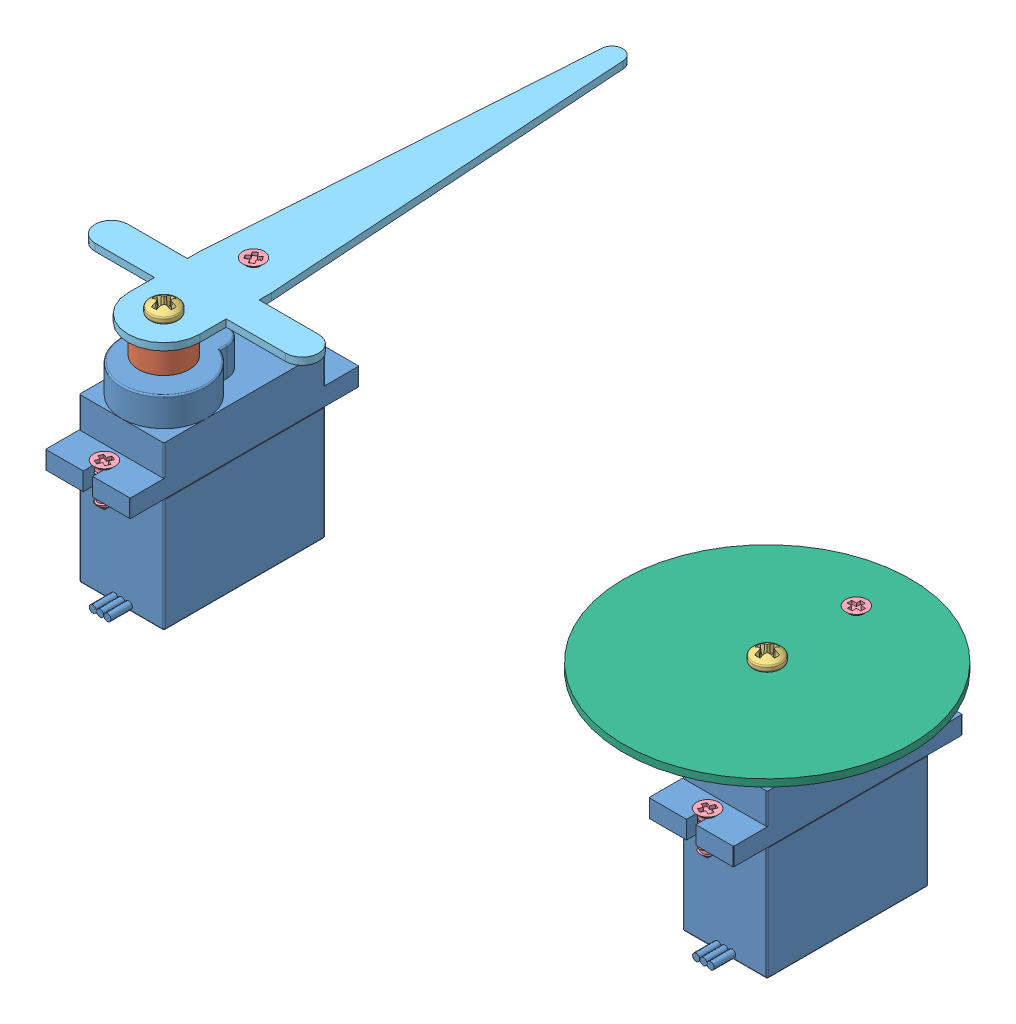
SolidWorks assembly AC, configuration Predeterminado. Lengths in mm.
Overall size (119.83 34.06 84.1).
14 component instances, 6 part files, 24 mates.
Components (placement in the parent):
- sg90-1: sg90 [Default] at (182.9409 -195.7135 134.2781) x (0 0 -1) z (1 0 0) size (31.9 29.9 11.8)
- sg90-2: sg90 [Default] at (98.7972 -195.7135 134.2781) x (0 0 -1) z (1 0 0) size (31.9 29.9 11.8)
- SG90 plastic Horn-1: SG90 plastic Horn [Default] at (188.8409 -166.2635 128.3781) x (-0.029359 0 -0.999569) z (0.999569 0 -0.029359) size (19.4 4 7.07)
- SG90 plastic Horn-2: SG90 plastic Horn [Default] at (104.6972 -166.2635 128.3781) x (-0.012387 0 -0.999923) z (0.999923 0 -0.012387) size (19.4 4 7.07)
- (M2_3_mm)_90116A007_METRIC 316 SS PAN HEAD PHILLIPS MACHINE SCREW-1: (M2_3_mm)_90116A007_METRIC 316 SS PAN HEAD PHILLIPS MACHINE SCREW [90116A007] at (104.6972 -166.2635 128.3781) x (-1 0 0) z (0 1 0) size (4 4 4.68)
- (M2_3_mm)_90116A007_METRIC 316 SS PAN HEAD PHILLIPS MACHINE SCREW-2: (M2_3_mm)_90116A007_METRIC 316 SS PAN HEAD PHILLIPS MACHINE SCREW [90116A007] at (188.8409 -166.2635 128.3781) x (-1 0 0) z (0 1 0) size (4 4 4.68)
- M2x6 SelfTap Screw-1: M2x6 SelfTap Screw [Predeterminado] at (104.6972 -162.7635 115.8781) x (0.825172 0 -0.564882) z (0 1 0) size (3.4 3.28 6)
- M2x6 SelfTap Screw-2: M2x6 SelfTap Screw [Predeterminado] at (188.7787 -162.7635 115.8783) x (0.001298 0 -0.999999) z (0 1 0) size (3.4 3.28 6)
- M2x6 SelfTap Screw-3: M2x6 SelfTap Screw [Predeterminado] at (104.6972 -176.8135 109.3781) x (-0.923728 0 -0.383049) z (0 1 0) size (3.4 3.28 6)
- M2x6 SelfTap Screw-4: M2x6 SelfTap Screw [Predeterminado] at (104.6972 -176.8135 136.6781) x (-0.923728 0 -0.383049) z (0 1 0) size (3.4 3.28 6)
- M2x6 SelfTap Screw-5: M2x6 SelfTap Screw [Predeterminado] at (188.8409 -176.8135 136.6781) x (0.923728 0 0.383049) z (0 1 0) size (3.4 3.28 6)
- M2x6 SelfTap Screw-6: M2x6 SelfTap Screw [Predeterminado] at (188.8409 -176.8135 109.3781) x (0.923728 0 0.383049) z (0 1 0) size (3.4 3.28 6)
- Sword-1: Sword [Predeterminado] at (59.4912 -163.2635 112.6165) x (1 0 0) z (0 1 0) size (31.17 69 1)
- Shield-1: Shield [Predeterminado] at (233.9679 -164.2635 112.3919) x (-0.999988 0 0.004973) z (0 -1 0) size (40 40 1)
Mates (geometry in assembly coordinates):
- Coincidente272: coincident: plane of sg90-1 through (188.8409 -165.8135 128.3781) normal (0 1 0); plane of SG90 plastic Horn-1 through (188.8043 -165.8135 127.1336) normal (0 -1 0)
- Concéntrica139: concentric: circle of sg90-1; circle of SG90 plastic Horn-1
- Concéntrica159: concentric: circle of sg90-1; circle of M2x6 SelfTap Screw-5
- Distancia35: distance = 0.5 mm: plane of M2x6 SelfTap Screw-5 through (188.8409 -176.8135 136.6781) normal (0 1 0); plane of sg90-1 through (182.9409 -177.3135 138.9781) normal (0 1 0)
- Concéntrica160: concentric: circle of sg90-1; circle of M2x6 SelfTap Screw-6
- Distancia36: distance = 0.5 mm: plane of M2x6 SelfTap Screw-6 through (188.8409 -176.8135 109.3781) normal (0 1 0); plane of sg90-1 through (194.7409 -177.3135 107.0781) normal (0 1 0)
- Coincidente273: coincident: plane of sg90-2 through (104.6972 -165.8135 128.3781) normal (0 1 0); plane of SG90 plastic Horn-2 through (104.6818 -165.8135 127.1332) normal (0 -1 0)
- Concéntrica140: concentric: circle of sg90-2; circle of SG90 plastic Horn-2
- Concéntrica161: concentric: circle of sg90-2; circle of M2x6 SelfTap Screw-4
- Distancia37: distance = 0.5 mm: plane of M2x6 SelfTap Screw-4 through (104.6972 -176.8135 136.6781) normal (0 1 0); plane of sg90-2 through (98.7972 -177.3135 138.9781) normal (0 1 0)
- Distancia38: distance = 0.5 mm: plane of M2x6 SelfTap Screw-3 through (104.6972 -176.8135 109.3781) normal (0 1 0); plane of sg90-2 through (110.5972 -177.3135 107.0781) normal (0 1 0)
- Concéntrica162: concentric: circle of sg90-2; circle of M2x6 SelfTap Screw-3
- Coincidente325: coincident: plane of SG90 plastic Horn-1 through (188.7371 -164.2635 124.8446) normal (0 1 0); plane of Shield-1 through (188.8409 -164.2635 128.3781) normal (0 -1 0)
- Concéntrica165: concentric: circle of SG90 plastic Horn-1; circle of Shield-1
- Coincidente323: coincident: plane of SG90 plastic Horn-2 through (104.6534 -164.2635 124.8434) normal (0 1 0); plane of Sword-1 through (91.4014 -164.2635 122.3945) normal (0 -1 0)
- Concéntrica163: concentric: circle of SG90 plastic Horn-2; circle of Sword-1
- Coincidente324: coincident: plane of (M2_3_mm)_90116A007_METRIC 316 SS PAN HEAD PHILLIPS MACHINE SCREW-1 through (104.6972 -163.2635 128.3781) normal (0 -1 0); plane of Sword-1 through (91.4014 -163.2635 122.3945) normal (0 1 0)
- Concéntrica164: concentric: circle of (M2_3_mm)_90116A007_METRIC 316 SS PAN HEAD PHILLIPS MACHINE SCREW-1; circle of Sword-1
- Coincidente327: coincident: plane of (M2_3_mm)_90116A007_METRIC 316 SS PAN HEAD PHILLIPS MACHINE SCREW-2 through (188.8409 -163.2635 128.3781) normal (0 -1 0); plane of Shield-1 through (188.8409 -163.2635 128.3781) normal (0 1 0)
- Concéntrica167: concentric: circle of (M2_3_mm)_90116A007_METRIC 316 SS PAN HEAD PHILLIPS MACHINE SCREW-2; circle of Shield-1
- Concéntrica168: concentric: circle of M2x6 SelfTap Screw-1; circle of Sword-1
- Distancia40: distance = 0.5 mm: plane of M2x6 SelfTap Screw-1 through (104.6972 -162.7635 115.8781) normal (0 1 0); plane of Sword-1 through (91.4014 -163.2635 122.3945) normal (0 1 0)
- Concéntrica166: concentric: circle of M2x6 SelfTap Screw-2; circle of Shield-1
- Distancia39: distance = 0.5 mm: plane of M2x6 SelfTap Screw-2 through (188.7787 -162.7635 115.8783) normal (0 1 0); plane of Shield-1 through (188.8409 -163.2635 128.3781) normal (0 1 0)
